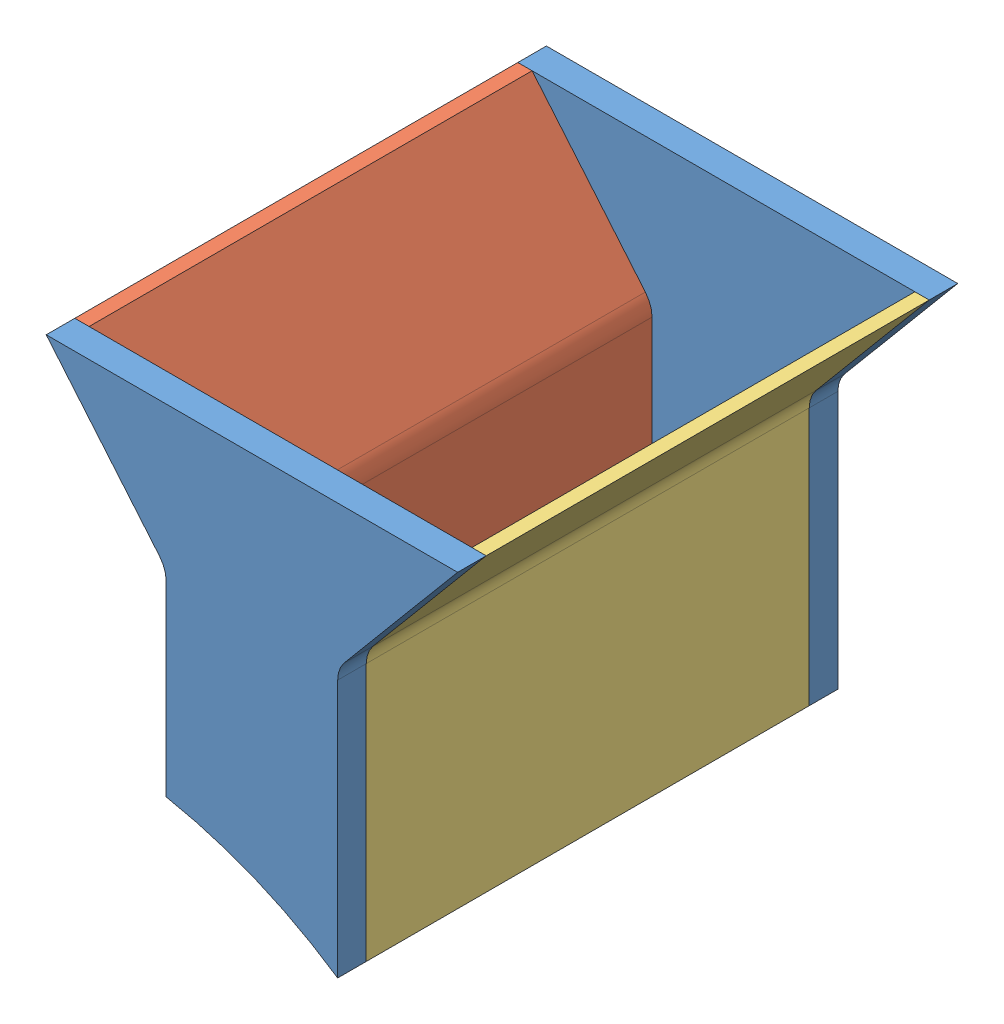
SolidWorks assembly 2.10 funnel assembly, configuration Default. Lengths in mm.
Overall size (143.95 143.92 175).
4 component instances, 3 part files, 9 mates.
Components (placement in the parent):
- 2.10 Funnel Side Panel-1: 2.10 Funnel Side Panel [Default] at (65.1075 36.9649 130.4117) size (143.95 143.92 10)
- 2.10 Funnel Side Panel-2: 2.10 Funnel Side Panel [Default] at (65.1075 36.9649 295.4117) size (143.95 143.92 10)
- 2.10 Funnel Left Side-1: 2.10 Funnel Left Side [Default] at (40.1075 60.8275 140.4117) size (46.97 120.06 155)
- 2.10 Funnel Right Side-1: 2.10 Funnel Right Side [Default] at (95.1075 36.9649 140.4117) size (71.24 143.92 155)
Mates (geometry in assembly coordinates):
- Coincident1: coincident anti-aligned: plane of 2.10 Funnel Side Panel-1 through (5.1075 -95.3226 140.4117) normal (0 0 1); plane of 2.10 Funnel Right Side-1 through (5.1075 -95.3226 140.4117) normal (0 0 -1)
- Coincident2: coincident aligned: line of 2.10 Funnel Side Panel-1 through (95.1075 36.9649 140.4117) axis (0 1 0); line of 2.10 Funnel Right Side-1 through (95.1075 36.9649 140.4117) axis (0 1 0)
- Coincident3: coincident: point of 2.10 Funnel Side Panel-1; moEndPointRef_w of 2.10 Funnel Right Side-1
- Coincident4: coincident anti-aligned: plane of 2.10 Funnel Side Panel-1 through (5.1075 -95.3226 140.4117) normal (0 0 1); plane of 2.10 Funnel Left Side-1 through (5.1075 -95.2974 140.4117) normal (0 0 -1)
- Coincident5: coincident aligned: line of 2.10 Funnel Side Panel-1 through (35.1075 127.2252 140.4117) axis (0 -1 0); line of 2.10 Funnel Left Side-1 through (35.1075 127.2252 140.4117) axis (0 -1 0)
- Coincident6: coincident aligned: line of 2.10 Funnel Side Panel-1 through (137.0815 180.8876 140.4117) axis (-1 0 0); line of 2.10 Funnel Left Side-1 through (-1.8665 180.8876 140.4117) axis (-1 0 0)
- Coincident7: coincident anti-aligned: plane of 2.10 Funnel Side Panel-2 through (5.1075 -95.3226 295.4117) normal (0 0 -1); plane of 2.10 Funnel Right Side-1 through (5.1075 -95.3226 295.4117) normal (0 0 1)
- Coincident9: coincident aligned: plane of 2.10 Funnel Side Panel-2 through (-6.8665 180.8876 305.4117) normal (0 1 0); plane of 2.10 Funnel Right Side-1 through (137.0815 180.8876 295.4117) normal (0 1 0)
- Coincident10: coincident aligned: plane of 2.10 Funnel Side Panel-2 through (95.1075 36.9649 305.4117) normal (1 0 0); plane of 2.10 Funnel Right Side-1 through (95.1075 36.9649 295.4117) normal (1 0 0)
